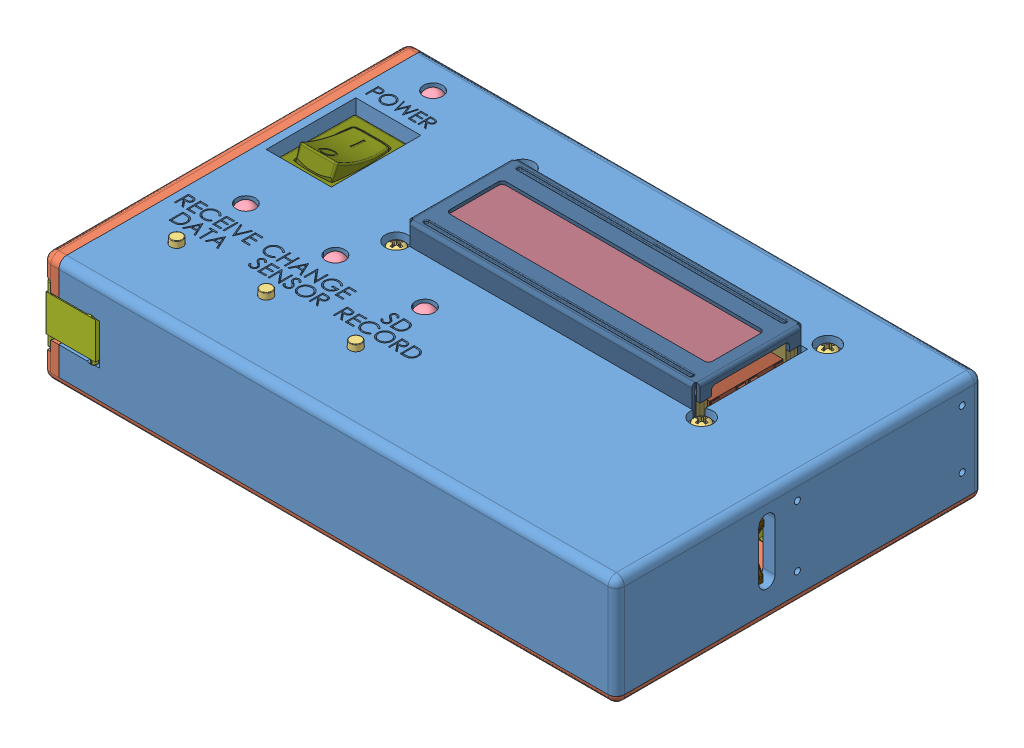
SolidWorks assembly Main Box assem, configuration Default. Lengths in mm.
Overall size (141 46.46 90).
79 component instances, 29 part files, 85 mates.
Components (placement in the parent):
- Main casing-1: Main casing [Default] at (-4.3813 58.0015 119.2261) size (137 25 90)
- Main Box Lid-1: Main Box Lid [Default] at (-5.329 58.0015 29.2261) x (0 -1 0) z (0 0 1) size (27 141 90)
- tactileswitch-short-1: tactileswitch-short [Default] at (31.6187 78.3185 101.2261) size (7.69 9.6 6.01)
- tactileswitch-short-2: tactileswitch-short [Default] at (53.6187 78.3185 101.2261) size (7.69 9.6 6.01)
- tactileswitch-short-3: tactileswitch-short [Default] at (9.6187 78.3185 101.2261) size (7.69 9.6 6.01)
- Led RGB 5mm-1: Led RGB 5mm [Valor predeterminado] at (53.6187 69.5015 84.2261) size (5.6 15.8 5.8)
  - Lente^Led RGB 5mm-1: Lente^Led RGB 5mm [Valor predeterminado] at origin size (5.6 8.8 5.8) (virtual)
  - Terminais^Led RGB 5mm-1: Terminais^Led RGB 5mm [Valor predeterminado] at origin size (4.82 11.92 1.55) (virtual)
- Led RGB 5mm-2: Led RGB 5mm [Valor predeterminado] at (31.6187 69.5015 84.2261) x (-0.356036 0 0.934472) z (-0.934472 0 -0.356036) size (5.6 15.8 5.8)
  - Lente^Led RGB 5mm-1: Lente^Led RGB 5mm [Valor predeterminado] at origin size (5.6 8.8 5.8) (virtual)
  - Terminais^Led RGB 5mm-1: Terminais^Led RGB 5mm [Valor predeterminado] at origin size (4.82 11.92 1.55) (virtual)
- Led RGB 5mm-3: Led RGB 5mm [Valor predeterminado] at (9.6187 69.5015 84.2261) size (5.6 15.8 5.8)
  - Lente^Led RGB 5mm-1: Lente^Led RGB 5mm [Valor predeterminado] at origin size (5.6 8.8 5.8) (virtual)
  - Terminais^Led RGB 5mm-1: Terminais^Led RGB 5mm [Valor predeterminado] at origin size (4.82 11.92 1.55) (virtual)
- Led RGB 5mm-4: Led RGB 5mm [Valor predeterminado] at (8.6187 69.3899 37.2261) x (0.999996 0 -0.002937) z (0.002937 0 0.999996) size (5.6 15.8 5.8)
  - Lente^Led RGB 5mm-1: Lente^Led RGB 5mm [Valor predeterminado] at origin size (5.6 8.8 5.8) (virtual)
  - Terminais^Led RGB 5mm-1: Terminais^Led RGB 5mm [Valor predeterminado] at origin size (4.82 11.92 1.55) (virtual)
- 9V-battery-1: 9V-battery [Default] at (40.7963 80.0125 82.5757) x (0 0 -1) z (-0.008727 -0.999962 0) size (26.04 47.88 17.14)
- Arduino Nano 33 IoT-1: Arduino Nano 33 IoT [Default] at (131.0969 70.3815 54.9561) x (0 -1 0) z (0 0 -1) size (17.78 5.55 45.32)
- LCD-1: LCD [Default] at (73.3362 78.3015 58.1261) size (80.01 18.33 36.01)
  - LCD.IGS-1: LCD.IGS [Default] at origin size (80.01 18.33 36.01)
    - pcbboard.IGS-1: pcbboard.IGS [Default] at origin size (80.01 4.2 36.01)
    - 16pin_header__.IGS-1: 16pin_header__.IGS [Default] at (-32 0 -15.5) x (0 0 1) z (1 0 0) size (2.55 11.51 40.65)
    - lcd window.IGS-1: lcd window.IGS [Default] at (0 9 1.5) size (71.31 11.83 27.45)
    - backlight.IGS-1: backlight.IGS [Default] at (0 1.7 1.5) x (-1 0 0) z (0 0 -1) size (74.39 2.99 18.01)
    - conductor.IGS-1: conductor.IGS [Default] at (0 1.7 12.6) size (69.71 5.51 3.01)
    - conductor.IGS-2: conductor.IGS [Default] at (0 1.7 -9.6) size (69.71 5.51 3.01)
    - liquid crystal grabcad.IGS-1: liquid crystal grabcad.IGS [Default] at (0 7.9 1.5) size (68.51 2.21 25.01)
    - smt_resistor222.IGS-1: smt_resistor222.IGS [Default] at (-32.75 0 -5.25) x (0 0 1) z (1 0 0) size (1.91 0.66 4.11)
    - smt_resistor222.IGS-2: smt_resistor222.IGS [Default] at (-32.75 0 -2.75) x (0 0 1) z (1 0 0) size (1.91 0.66 4.11)
    - smt_resistor222.IGS-3: smt_resistor222.IGS [Default] at (-32.75 0 -0.25) x (0 0 1) z (1 0 0) size (1.91 0.66 4.11)
    - smt_resistor222.IGS-4: smt_resistor222.IGS [Default] at (-32.75 0 2.25) x (0 0 1) z (1 0 0) size (1.91 0.66 4.11)
    - smt_resistor222.IGS-5: smt_resistor222.IGS [Default] at (-32.75 0 4.75) x (0 0 1) z (1 0 0) size (1.91 0.66 4.11)
    - smt_resistor222.IGS-6: smt_resistor222.IGS [Default] at (-32.75 0 7.25) x (0 0 1) z (1 0 0) size (1.91 0.66 4.11)
    - smt_resistor101.IGS-1: smt_resistor101.IGS [Default] at (30.25 0 6.1) x (0 0 -1) z (-1 0 0) size (1.91 0.66 5.31)
    - smt_resistor101.IGS-2: smt_resistor101.IGS [Default] at (30.25 0 2.85) x (0 0 -1) z (-1 0 0) size (1.91 0.66 5.31)
- rocker switch 1-1: rocker switch 1 [test] at (8.4333 80.3594 59.2279) x (1 0 0) z (0 0.999962 -0.008727) size (15 21 21.16)
- MicroSD Card Module - 1-1: MicroSD Card Module - 1 [Default] at (123.1318 70.6792 85.4943) x (0.008726 0.999924 -0.008727) z (-0.000076 -0.008726 -0.999962) size (18.11 20.62 3.45)
  - MicroSD Card Module - 1.stp-1: MicroSD Card Module - 1.stp [Default] at origin size (18.11 20.62 3.45)
    - Micro SD Module - 1.stp-1: Micro SD Module - 1.stp [Default] at origin size (18.11 18.08 1.84)
    - MicroSD.stp-1: MicroSD.stp [Default] at (0 5.5324 1.6764) x (-1 0 0) z (0 1 0) size (14.1 2.25 13.6)
    - 0603 Capacitor.stp-1: 0603 Capacitor.stp [Default] at (-4.7839 -5.8092 1.6739) x (0 1 0) z (0 0 1) size (1.6 0.84 0.84)
    - 0603 Resistor.stp-1: 0603 Resistor.stp [Default] at (-1.2256 -4.214 1.6739) x (0 -1 0) z (0 0 1) size (1.6 0.85 0.56)
    - 0603 Capacitor.stp-2: 0603 Capacitor.stp [Default] at (-2.9282 -5.8092 1.6739) x (0 1 0) z (0 0 1) size (1.6 0.84 0.84)
    - 0603 Resistor.stp-2: 0603 Resistor.stp [Default] at (0.7739 -4.214 1.6739) x (0 -1 0) z (0 0 1) size (1.6 0.85 0.56)
    - 0603 Resistor.stp-3: 0603 Resistor.stp [Default] at (2.7155 -4.214 1.6739) x (0 -1 0) z (0 0 1) size (1.6 0.85 0.56)
    - 0603 Resistor.stp-4: 0603 Resistor.stp [Default] at (4.6861 -4.214 1.6739) x (0 -1 0) z (0 0 1) size (1.6 0.85 0.56)
- pan_head_phillip_mc_screw_m2-2: pan_head_phillip_mc_screw_m2 [Default] at (36.1187 81.0015 42.7261) size (4 9.78 4)
- pan_head_phillip_mc_screw_m2-3: pan_head_phillip_mc_screw_m2 [Default] at (36.1187 81.0015 73.7261) size (4 9.78 4)
- pan_head_phillip_mc_screw_m2-4: pan_head_phillip_mc_screw_m2 [Default] at (111.1187 81.0015 42.7261) size (4 9.78 4)
- pan_head_phillip_mc_screw_m2-5: pan_head_phillip_mc_screw_m2 [Default] at (111.1187 81.0015 73.7261) size (4 9.78 4)
- m2_screw_size_flat_washer-1: m2_screw_size_flat_washer [Default] at (111.1187 77.7035 42.7261) x (1 0 0) z (0 -1 0) size (5 5 0.4)
- m2_screw_size_flat_washer-2: m2_screw_size_flat_washer [Default] at (36.1187 78.3015 42.7261) x (0.926157 0 -0.377138) z (0 -1 0) size (5 5 0.4)
- m2_screw_size_flat_washer-3: m2_screw_size_flat_washer [Default] at (36.1187 78.3015 73.7261) x (1 0 0) z (0 -1 0) size (5 5 0.4)
- m2_screw_size_flat_washer-4: m2_screw_size_flat_washer [Default] at (111.1187 78.2015 73.7261) x (1 0 0) z (0 -1 0) size (5 5 0.4)
- M2-1: M2 [Default] at (111.1187 75.7035 42.7261) x (0.460049 0 0.887894) z (0 -1 0) size (4.62 4.63 1.61)
- M2-2: M2 [Default] at (111.1187 76.2015 73.7261) x (1 0 0) z (0 -1 0) size (4.62 4.63 1.61)
- M2-3: M2 [Default] at (36.1187 76.3015 73.7261) x (1 0 0) z (0 -1 0) size (4.62 4.63 1.61)
- M2-4: M2 [Default] at (36.1187 76.3015 42.7261) x (1 0 0) z (0 -1 0) size (4.62 4.63 1.61)
- pan_head_philip_mc_screw_m1-6-1: pan_head_philip_mc_screw_m1-6 [Default] at (130.2969 63.3095 34.2264) x (0 1 0) z (0 0 1) size (3.2 5.49 3.2)
- pan_head_philip_mc_screw_m1-6-2: pan_head_philip_mc_screw_m1-6 [Default] at (130.2969 78.5495 34.2264) x (0 1 0) z (0 0 1) size (3.2 5.49 3.2)
- pan_head_philip_mc_screw_m1-6-3: pan_head_philip_mc_screw_m1-6 [Default] at (130.2969 63.3095 74.8664) x (0 1 0) z (0 0 1) size (3.2 5.49 3.2)
- pan_head_philip_mc_screw_m1-6-4: pan_head_philip_mc_screw_m1-6 [Default] at (130.2969 78.0015 74.8661) x (0 0.069377 -0.997591) z (0 0.997591 0.069377) size (3.2 5.49 3.2)
- Box Locking Part-1: Box Locking Part [Default] at (7.4072 65.5015 30.9356) x (-0.998613 0 0.052659) z (0 -1 0) size (12.2 1.5 14)
- Box Locking Part-2: Box Locking Part [Default] at (7.3705 65.5015 118.9743) x (-0.999997 0 0.002417) z (0 -1 0) size (12.2 1.5 14)
- Belt clip-1: Belt clip [Default] at (75.171 53.0015 45.7127) x (0 -1 0) z (1 0 0) size (14.34 51.37 20)
- Belt clip-2: Belt clip [Default] at (35.171 53.0015 45.7127) x (0 -1 0) z (1 0 0) size (14.34 51.37 20)
- !!__83-1: !!__83 [По умолчанию] at (90.171 54.5015 55.2123) x (-1 0 0) z (0 0 1) size (7 12 7)
- !!__83-2: !!__83 [По умолчанию] at (80.171 54.5015 55.2123) x (-0.998428 0 -0.056053) z (-0.056053 0 0.998428) size (7 12 7)
- !!__83-3: !!__83 [По умолчанию] at (50.171 54.5015 55.2123) x (-1 0 0) z (0 0 1) size (7 12 7)
- !!__83-4: !!__83 [По умолчанию] at (40.171 54.5015 55.2123) x (-1 0 0) z (0 0 1) size (7 12 7)
- flat_washer_M4x9-1: flat_washer_M4x9 [Default] at (40.171 58.8015 55.2123) x (-0.969713 0 -0.244247) z (0 -1 0) size (9 9 0.8)
- flat_washer_M4x9-2: flat_washer_M4x9 [Default] at (50.171 58.8015 55.2123) x (-0.666272 0 0.745709) z (0 -1 0) size (9 9 0.8)
- flat_washer_M4x9-3: flat_washer_M4x9 [Default] at (80.171 58.0015 55.2123) x (0.999002 0 0.044669) z (0 1 0) size (9 9 0.8)
- flat_washer_M4x9-4: flat_washer_M4x9 [Default] at (90.171 58.0015 55.2123) x (-0.211139 0 0.977456) z (0 1 0) size (9 9 0.8)
- hexagonal_nut_reduced_height_M4-1: hexagonal_nut_reduced_height_M4 [Default] at (40.171 61.6015 55.2123) x (0.91494 0 -0.40359) z (0 -1 0) size (8.08 7 2.8)
- hexagonal_nut_reduced_height_M4-2: hexagonal_nut_reduced_height_M4 [Default] at (50.171 61.6015 55.2123) x (0 0 1) z (0 -1 0) size (8.08 7 2.8)
- hexagonal_nut_reduced_height_M4-3: hexagonal_nut_reduced_height_M4 [Default] at (80.171 61.6015 55.2123) x (0.898123 0 0.439743) z (0 -1 0) size (8.08 7 2.8)
- hexagonal_nut_reduced_height_M4-4: hexagonal_nut_reduced_height_M4 [Default] at (90.171 61.6015 55.2123) x (0.372097 0 0.928194) z (0 -1 0) size (8.08 7 2.8)
Mates (geometry in assembly coordinates):
- Parallel1: parallel aligned: plane of Main casing-1 through (-4.3813 83.0015 29.2261) normal (0 0 -1); plane of Main Box Lid-1 through (-1.329 58.0015 29.2261) normal (0 0 -1)
- Coincident2: coincident anti-aligned: plane of Main casing-1 through (-4.3813 82.0015 119.2261) normal (0 -1 0); plane of tactileswitch-short-1 through (28.7421 82.0015 104.1027) normal (0 1 0)
- Concentric1: concentric aligned: cylinder of Main casing-1 through (31.6187 78.5015 101.2261) axis (0 1 0) radius 1.5; cone of tactileswitch-short-1 through (31.6187 82.0015 101.2261) axis (0 1 0)
- Coincident3: coincident anti-aligned: plane of Main casing-1 through (-4.3813 82.0015 119.2261) normal (0 -1 0); plane of tactileswitch-short-2 through (50.7421 82.0015 104.1027) normal (0 1 0)
- Concentric2: concentric aligned: cylinder of Main casing-1 through (53.6187 78.5015 101.2261) axis (0 1 0) radius 1.5; cone of tactileswitch-short-2 through (53.6187 82.0015 101.2261) axis (0 1 0)
- Coincident4: coincident anti-aligned: plane of Main casing-1 through (-4.3813 82.0015 119.2261) normal (0 -1 0); plane of tactileswitch-short-3 through (6.7421 82.0015 104.1027) normal (0 1 0)
- Concentric3: concentric aligned: cylinder of Main casing-1 through (9.6187 78.5015 101.2261) axis (0 1 0) radius 1.5; cone of tactileswitch-short-3 through (9.6187 82.0015 101.2261) axis (0 1 0)
- Concentric4: concentric anti-aligned: cone of Main casing-1 through (8.6187 83.0015 37.2261) axis (0 1 0); cylinder of Led RGB 5mm-4/Lente^Led RGB 5mm-1 through (8.6187 83.1899 37.2261) axis (0 -1 0) radius 2.5
- Parallel4: parallel aligned: cone of Main casing-1 through (9.6187 83.0015 84.2261) axis (0 1 0); line of Led RGB 5mm-3/Terminais^Led RGB 5mm-1 through (8.6687 67.5015 83.9261) axis (0 1 0)
- Concentric5: concentric anti-aligned: cone of Main casing-1 through (9.6187 83.0015 84.2261) axis (0 1 0); cylinder of Led RGB 5mm-3/Lente^Led RGB 5mm-1 through (9.6187 83.3015 84.2261) axis (0 -1 0) radius 2.5
- Coincident6: coincident anti-aligned: plane of Main casing-1 through (9.6187 75.5015 84.2261) normal (0 -1 0); plane of Led RGB 5mm-3/Lente^Led RGB 5mm-1 through (9.6187 75.5015 84.2261) normal (0 1 0)
- Concentric6: concentric anti-aligned: cone of Main casing-1 through (31.6187 83.0015 84.2261) axis (0 1 0); cylinder of Led RGB 5mm-2/Lente^Led RGB 5mm-1 through (31.6187 83.3015 84.2261) axis (0 -1 0) radius 2.5
- Coincident7: coincident anti-aligned: plane of Main casing-1 through (31.6187 75.5015 84.2261) normal (0 -1 0); plane of Led RGB 5mm-2/Lente^Led RGB 5mm-1 through (31.6187 75.5015 84.2261) normal (0 1 0)
- Concentric7: concentric anti-aligned: cone of Main casing-1 through (53.6187 83.0015 84.2261) axis (0 1 0); cylinder of Led RGB 5mm-1/Lente^Led RGB 5mm-1 through (53.6187 83.3015 84.2261) axis (0 -1 0) radius 2.5
- Coincident8: coincident anti-aligned: plane of Main casing-1 through (53.6187 75.5015 84.2261) normal (0 -1 0); plane of Led RGB 5mm-1/Lente^Led RGB 5mm-1 through (53.6187 75.5015 84.2261) normal (0 1 0)
- Distance1: distance = 0 mm anti-aligned: plane of Main Box Lid-1 through (135.671 58.0015 119.2261) normal (0 1 0); plane of Main casing-1 through (-4.3813 58.0015 119.2261) normal (0 -1 0)
- Distance3: distance = 0 mm aligned: plane of Main Box Lid-1 through (-1.329 58.0015 29.2261) normal (0 0 -1); plane of Main casing-1 through (-4.3813 83.0015 29.2261) normal (0 0 -1)
- Coincident13: coincident anti-aligned: plane of Main casing-1 through (36.1187 81.0015 42.7261) normal (0 1 0); plane of pan_head_phillip_mc_screw_m2-2 through (36.1187 81.0015 42.7261) normal (0 -1 0)
- Concentric8: concentric aligned: circle of Main casing-1; circle of pan_head_phillip_mc_screw_m2-2
- Coincident14: coincident anti-aligned: plane of Main casing-1 through (36.1187 81.0015 73.7261) normal (0 1 0); plane of pan_head_phillip_mc_screw_m2-3 through (36.1187 81.0015 73.7261) normal (0 -1 0)
- Concentric9: concentric aligned: circle of Main casing-1; circle of pan_head_phillip_mc_screw_m2-3
- Coincident15: coincident anti-aligned: plane of Main casing-1 through (-4.3813 81.0015 119.2261) normal (0 1 0); plane of pan_head_phillip_mc_screw_m2-5 through (111.1187 81.0015 73.7261) normal (0 -1 0)
- Concentric10: concentric aligned: circle of Main casing-1; circle of pan_head_phillip_mc_screw_m2-5
- Coincident16: coincident anti-aligned: plane of Main casing-1 through (-4.3813 81.0015 119.2261) normal (0 1 0); plane of pan_head_phillip_mc_screw_m2-4 through (111.1187 81.0015 42.7261) normal (0 -1 0)
- Concentric11: concentric aligned: circle of Main casing-1; circle of pan_head_phillip_mc_screw_m2-4
- Concentric12: concentric anti-aligned: cylinder of Main casing-1 through (111.1187 58.0015 42.7261) axis (0 1 0) radius 1.25; cylinder of m2_screw_size_flat_washer-1 through (111.1187 77.3035 42.7261) axis (0 -1 0) radius 1.1
- Concentric13: concentric anti-aligned: circle of Main casing-1; circle of M2-1
- Coincident17: coincident anti-aligned: plane of m2_screw_size_flat_washer-1 through (111.1187 77.3035 42.7261) normal (0 -1 0); plane of M2-1 through (109.0682 77.3035 43.7886) normal (0 1 0)
- Concentric14: concentric aligned: circle of Main casing-1; circle of m2_screw_size_flat_washer-2
- Tangent3: tangent anti-aligned: plane of Main casing-1 through (-4.3813 80.0015 119.2261) normal (0 -1 0); face of LCD-1/LCD.IGS-1/pcbboard.IGS-1
- Tangent4: tangent anti-aligned: plane of Main casing-1 through (-4.3813 58.0015 46.2261) normal (0 0 1); edge_curve of LCD-1/LCD.IGS-1/lcd window.IGS-1
- Tangent5: tangent: edge_curve of LCD-1/LCD.IGS-1/pcbboard.IGS-1; plane of m2_screw_size_flat_washer-2 through (36.1187 78.3015 42.7261) normal (0 1 0)
- Coincident18: coincident anti-aligned: plane of m2_screw_size_flat_washer-2 through (36.1187 77.9015 42.7261) normal (0 -1 0); plane of M2-4 through (36.1187 77.9015 45.0355) normal (0 1 0)
- Concentric15: concentric anti-aligned: circle of Main casing-1; circle of M2-4
- Tangent6: tangent: plane of assembly; face of LCD-1/LCD.IGS-1/pcbboard.IGS-1; plane of m2_screw_size_flat_washer-3 through (36.1187 78.3015 73.7261) normal (0 1 0)
- Concentric16: concentric aligned: circle of Main casing-1; circle of m2_screw_size_flat_washer-3
- Coincident19: coincident anti-aligned: plane of m2_screw_size_flat_washer-3 through (36.1187 77.9015 73.7261) normal (0 -1 0); plane of M2-3 through (36.1187 77.9015 76.0355) normal (0 1 0)
- Concentric17: concentric anti-aligned: circle of Main casing-1; circle of M2-3
- Tangent7: tangent: plane of assembly; face of LCD-1/LCD.IGS-1/pcbboard.IGS-1; plane of m2_screw_size_flat_washer-4 through (111.1187 78.2015 73.7261) normal (0 1 0)
- Concentric18: concentric aligned: circle of Main casing-1; circle of m2_screw_size_flat_washer-4
- Coincident20: coincident anti-aligned: plane of m2_screw_size_flat_washer-4 through (111.1187 77.8015 73.7261) normal (0 -1 0); plane of M2-2 through (111.1187 77.8015 76.0355) normal (0 1 0)
- Concentric19: concentric anti-aligned: circle of Main casing-1; circle of M2-2
- Coincident21: coincident anti-aligned: plane of Arduino Nano 33 IoT-1 through (130.2969 70.3815 54.9561) normal (-1 0 0); plane of pan_head_philip_mc_screw_m1-6-1 through (130.2969 63.3095 34.2264) normal (1 0 0)
- Tangent8: tangent: curve of Arduino Nano 33 IoT-1; edge_curve of pan_head_philip_mc_screw_m1-6-1
- Concentric20: concentric aligned: circle of Main casing-1; cylinder of Arduino Nano 33 IoT-1 through (177.7804 78.0015 34.2261) axis (-1 0 0) radius 0.8
- Coincident25: coincident anti-aligned: plane of Arduino Nano 33 IoT-1 through (130.2969 70.3815 54.9561) normal (-1 0 0); plane of pan_head_philip_mc_screw_m1-6-3 through (130.2969 63.3095 74.8664) normal (1 0 0)
- Tangent11: tangent: circle of Arduino Nano 33 IoT-1; edge_curve of pan_head_philip_mc_screw_m1-6-3
- Coincident26: coincident anti-aligned: plane of Arduino Nano 33 IoT-1 through (130.2969 70.3815 54.9561) normal (-1 0 0); plane of pan_head_philip_mc_screw_m1-6-2 through (130.2969 78.5495 34.2264) normal (1 0 0)
- Tangent12: tangent: circle of Arduino Nano 33 IoT-1; edge_curve of pan_head_philip_mc_screw_m1-6-2
- Coincident27: coincident anti-aligned: plane of Arduino Nano 33 IoT-1 through (130.2969 70.3815 54.9561) normal (-1 0 0); plane of pan_head_philip_mc_screw_m1-6-4 through (130.2969 78.0015 74.8661) normal (1 0 0)
- Concentric22: concentric aligned: circle of Arduino Nano 33 IoT-1; circle of pan_head_philip_mc_screw_m1-6-4
- Concentric23: concentric anti-aligned: cylinder of Main casing-1 through (6.6187 63.0015 30.2261) axis (0 1 0) radius 0.8753; cylinder of Box Locking Part-1 through (6.6187 76.0015 30.2261) axis (0 -1 0) radius 0.65
- Distance4: distance = 0.5 mm anti-aligned: plane of Box Locking Part-1 through (7.3282 74.5015 29.4377) normal (0 1 0); plane of Main casing-1 through (-1.3813 75.0015 31.2261) normal (0 -1 0)
- Concentric24: concentric anti-aligned: cylinder of Main casing-1 through (6.6187 63.0015 118.2261) axis (0 1 0) radius 0.875; cylinder of Box Locking Part-2 through (6.6187 76.0015 118.2261) axis (0 -1 0) radius 0.65
- Distance5: distance = 0.5 mm anti-aligned: plane of Box Locking Part-2 through (7.3669 74.5015 117.4743) normal (0 1 0); plane of Main casing-1 through (-1.3813 75.0015 117.2261) normal (0 -1 0)
- Coincident30: coincident anti-aligned: plane of Main Box Lid-1 through (-5.329 56.0015 29.2261) normal (0 -1 0); plane of Belt clip-1 through (95.171 56.0015 45.7127) normal (0 1 0)
- Concentric25: concentric anti-aligned: cylinder of Main Box Lid-1 through (90.171 66.0015 55.2123) axis (0 -1 0) radius 2.5; cylinder of Belt clip-1 through (90.171 36.0015 55.2123) axis (0 1 0) radius 2
- Concentric26: concentric anti-aligned: cylinder of Main Box Lid-1 through (80.171 66.0015 55.2123) axis (0 -1 0) radius 2.5; cylinder of Belt clip-1 through (80.171 36.0015 55.2123) axis (0 1 0) radius 2
- Coincident31: coincident anti-aligned: plane of Main Box Lid-1 through (-5.329 56.0015 29.2261) normal (0 -1 0); plane of Belt clip-2 through (55.171 56.0015 45.7127) normal (0 1 0)
- Concentric27: concentric anti-aligned: cylinder of Main Box Lid-1 through (50.171 66.0015 55.2123) axis (0 -1 0) radius 2.5; cylinder of Belt clip-2 through (50.171 36.0015 55.2123) axis (0 1 0) radius 2
- Concentric28: concentric anti-aligned: cylinder of Main Box Lid-1 through (40.171 66.0015 55.2123) axis (0 -1 0) radius 2.5; cylinder of Belt clip-2 through (40.171 36.0015 55.2123) axis (0 1 0) radius 2
- Coincident32: coincident anti-aligned: cylinder of Belt clip-1 through (90.171 36.0015 55.2123) axis (0 1 0) radius 2; circle of !!__83-1
- Coincident33: coincident anti-aligned: plane of Belt clip-1 through (90.171 54.5015 55.2123) normal (0 -1 0); plane of !!__83-1 through (90.171 54.5015 55.2123) normal (0 1 0)
- Coincident34: coincident anti-aligned: cylinder of Belt clip-1 through (80.171 36.0015 55.2123) axis (0 1 0) radius 2; circle of !!__83-2
- Coincident35: coincident anti-aligned: plane of Belt clip-1 through (75.171 54.5015 45.7127) normal (0 -1 0); plane of !!__83-2 through (80.171 54.5015 55.2123) normal (0 1 0)
- Coincident36: coincident anti-aligned: cylinder of Belt clip-2 through (50.171 36.0015 55.2123) axis (0 1 0) radius 2; circle of !!__83-3
- Coincident37: coincident anti-aligned: plane of Belt clip-2 through (50.171 54.5015 55.2123) normal (0 -1 0); plane of !!__83-3 through (50.171 54.5015 55.2123) normal (0 1 0)
- Coincident38: coincident anti-aligned: cylinder of Belt clip-2 through (40.171 36.0015 55.2123) axis (0 1 0) radius 2; circle of !!__83-4
- Coincident39: coincident anti-aligned: plane of Belt clip-2 through (35.171 54.5015 45.7127) normal (0 -1 0); plane of !!__83-4 through (40.171 54.5015 55.2123) normal (0 1 0)
- Concentric29: concentric aligned: circle of Main Box Lid-1; circle of flat_washer_M4x9-1
- Coincident40: coincident anti-aligned: plane of Main Box Lid-1 through (135.671 58.0015 119.2261) normal (0 1 0); plane of flat_washer_M4x9-1 through (40.171 58.0015 55.2123) normal (0 -1 0)
- Concentric30: concentric aligned: circle of flat_washer_M4x9-1; cylinder of hexagonal_nut_reduced_height_M4-1 through (40.171 61.2551 55.2123) axis (0 -1 0) radius 2
- Coincident41: coincident anti-aligned: plane of flat_washer_M4x9-1 through (40.171 58.8015 55.2123) normal (0 1 0); plane of hexagonal_nut_reduced_height_M4-1 through (40.171 58.8015 55.2123) normal (0 -1 0)
- Concentric31: concentric aligned: cylinder of Main Box Lid-1 through (50.171 66.0015 55.2123) axis (0 -1 0) radius 2.5; circle of flat_washer_M4x9-2
- Coincident42: coincident anti-aligned: plane of Main Box Lid-1 through (135.671 58.0015 119.2261) normal (0 1 0); plane of flat_washer_M4x9-2 through (50.171 58.0015 55.2123) normal (0 -1 0)
- Concentric32: concentric aligned: circle of flat_washer_M4x9-2; cylinder of hexagonal_nut_reduced_height_M4-2 through (50.171 61.2551 55.2123) axis (0 -1 0) radius 2
- Coincident43: coincident anti-aligned: plane of flat_washer_M4x9-2 through (50.171 58.8015 55.2123) normal (0 1 0); plane of hexagonal_nut_reduced_height_M4-2 through (50.171 58.8015 55.2123) normal (0 -1 0)
- Concentric33: concentric anti-aligned: circle of Main Box Lid-1; circle of flat_washer_M4x9-3
- Coincident44: coincident anti-aligned: plane of Main Box Lid-1 through (135.671 58.0015 119.2261) normal (0 1 0); plane of flat_washer_M4x9-3 through (80.171 58.0015 55.2123) normal (0 -1 0)
- Concentric34: concentric anti-aligned: circle of flat_washer_M4x9-3; circle of hexagonal_nut_reduced_height_M4-3
- Coincident45: coincident anti-aligned: plane of flat_washer_M4x9-3 through (80.171 58.8015 55.2123) normal (0 1 0); plane of hexagonal_nut_reduced_height_M4-3 through (80.171 58.8015 55.2123) normal (0 -1 0)
- Concentric35: concentric anti-aligned: cylinder of Main Box Lid-1 through (90.171 66.0015 55.2123) axis (0 -1 0) radius 2.5; circle of flat_washer_M4x9-4
- Coincident46: coincident anti-aligned: plane of Main Box Lid-1 through (135.671 58.0015 119.2261) normal (0 1 0); plane of flat_washer_M4x9-4 through (90.171 58.0015 55.2123) normal (0 -1 0)
- Concentric36: concentric anti-aligned: circle of flat_washer_M4x9-4; cylinder of hexagonal_nut_reduced_height_M4-4 through (90.171 61.2551 55.2123) axis (0 -1 0) radius 2
- Coincident47: coincident anti-aligned: plane of flat_washer_M4x9-4 through (90.171 58.8015 55.2123) normal (0 1 0); plane of hexagonal_nut_reduced_height_M4-4 through (90.171 58.8015 55.2123) normal (0 -1 0)
